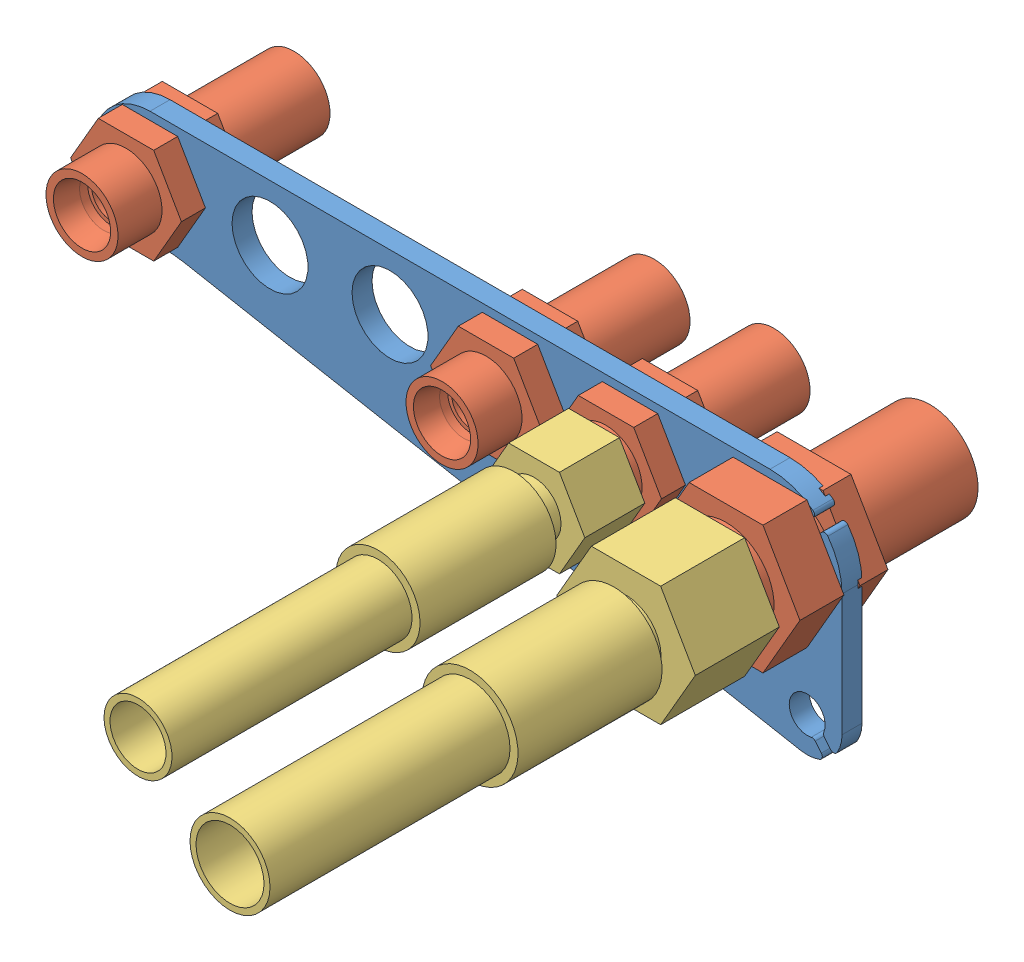
SolidWorks assembly Slangeholder_kpl, configuration Default. Lengths in mm.
Overall size (191.95 63.2 175).
7 component instances, 3 part files, 18 mates.
Components (placement in the parent):
- 6340315-2: 6340315 [Default] at origin size (186.76 57.2 5)
- Skotforskruninger-1: Skotforskruninger [GSS 12 L - 25201] at (120 0 5) size (27.71 24 53)
- Skotforskruninger-2: Skotforskruninger [GSS 12 L - 25201] at (90 0 5) size (27.71 24 53)
- Skotforskruninger-3: Skotforskruninger [P-GSV 16 S - 26335] at (155 -4 5) x (-0.5 0.866025 0) z (0 0 1) size (36.95 32 65)
- Slange ende lige-1: Slange ende lige [1-2] at (155 -4 20) x (0.866025 -0.5 0) z (0 0 1) size (30 34.64 120)
- Slange ende lige-2: Slange ende lige [3-8] at (120 0 14) x (0.866025 -0.5 0) z (0 0 1) size (22 25.4 114)
- Skotforskruninger-4: Skotforskruninger [GSS 12 L - 25201] at (0 0 5) size (27.71 24 53)
Mates (geometry in assembly coordinates):
- Concentric1: concentric aligned: cylinder of 6340315-2 through (120 0 5) axis (0 0 -1) radius 9.5; cylinder of Skotforskruninger-1 through (120 0 22) axis (0 0 -1) radius 9
- Coincident1: coincident anti-aligned: plane of 6340315-2 through (3.1735 -44 5) normal (0 0 1); plane of Skotforskruninger-1 through (133.8564 0 5) normal (0 0 -1)
- Concentric2: concentric aligned: cylinder of 6340315-2 through (90 0 5) axis (0 0 -1) radius 9.5; cylinder of Skotforskruninger-2 through (90 0 22) axis (0 0 -1) radius 9
- Coincident2: coincident anti-aligned: plane of 6340315-2 through (3.1735 -44 5) normal (0 0 1); plane of Skotforskruninger-2 through (103.8564 0 5) normal (0 0 -1)
- Concentric3: concentric aligned: cylinder of 6340315-2 through (155 -4 5) axis (0 0 -1) radius 12.25; cylinder of Skotforskruninger-3 through (155 -4 30) axis (0 0 -1) radius 12
- Coincident3: coincident anti-aligned: plane of 6340315-2 through (3.1735 -44 5) normal (0 0 1); plane of Skotforskruninger-3 through (145.7624 12 5) normal (0 0 -1)
- Parallel1: parallel aligned: plane of 6340315-2 through (0 14 5) normal (0 1 0); plane of Skotforskruninger-2 through (96.9282 12 11) normal (0 1 0)
- Parallel2: parallel aligned: plane of 6340315-2 through (0 14 5) normal (0 1 0); plane of Skotforskruninger-1 through (126.9282 12 11) normal (0 1 0)
- Parallel3: parallel aligned: plane of 6340315-2 through (0 14 5) normal (0 1 0); plane of Skotforskruninger-3 through (164.2376 12 16) normal (0 1 0)
- Concentric4: concentric aligned: cylinder of Skotforskruninger-3 through (155 -4 30) axis (0 0 -1) radius 12; cylinder of Slange ende lige-1 through (155 -4 80) axis (0 0 -1) radius 12
- Distance1: distance = 10 mm anti-aligned: plane of Skotforskruninger-3 through (155 -4 30) normal (0 0 1); plane of Slange ende lige-1 through (155 26 20) normal (0 0 -1)
- Concentric5: concentric aligned: cylinder of Skotforskruninger-1 through (120 0 22) axis (0 0 -1) radius 9; cylinder of Slange ende lige-2 through (120 0 68) axis (0 0 -1) radius 10.5
- Distance2: distance = 8 mm anti-aligned: plane of Skotforskruninger-1 through (120 0 22) normal (0 0 1); plane of Slange ende lige-2 through (126.3509 11 14) normal (0 0 -1)
- Parallel4: parallel aligned: plane of 6340315-2 through (0 14 5) normal (0 1 0); plane of Slange ende lige-2 through (126.3509 11 29) normal (0 1 0)
- Parallel5: parallel aligned: plane of 6340315-2 through (0 14 5) normal (0 1 0); plane of Slange ende lige-1 through (163.6603 11 41) normal (0 1 0)
- Concentric6: concentric anti-aligned: cylinder of 6340315-2 through (0 0 5) axis (0 0 -1) radius 9.5; cylinder of Skotforskruninger-4 through (0 0 -31) axis (0 0 1) radius 9
- Coincident8: coincident anti-aligned: plane of 6340315-2 through (3.1735 -44 5) normal (0 0 1); plane of Skotforskruninger-4 through (13.8564 0 5) normal (0 0 -1)
- Parallel6: parallel aligned: plane of 6340315-2 through (0 14 5) normal (0 1 0); plane of Skotforskruninger-4 through (-6.9282 12 -5) normal (0 1 0)
